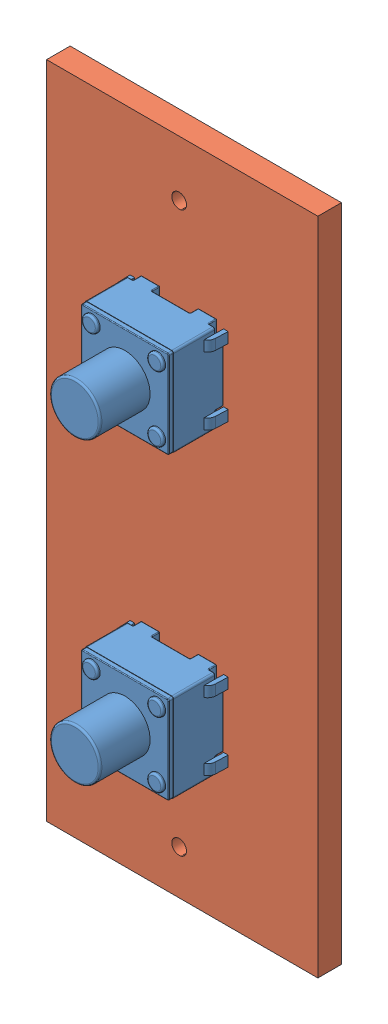
SolidWorks assembly tactile_switches, configuration Default. Lengths in mm.
Overall size (18.42 50 10.46).
3 component instances, 2 part files, 7 mates.
Components (placement in the parent):
- tactileswitch-short-1: tactileswitch-short [Default] at (-16.5128 4.5787 28.3133) x (1 0 0) z (0 -1 0) size (7.69 10.46 6.01)
- tactile_board-1: tactile_board [Default] at (-25.5128 -27.7413 26.7133) size (18.42 44.79 1.6)
- tactileswitch-short-2: tactileswitch-short [Default] at (-16.5128 -15.7413 28.3133) x (1 0 0) z (0 -1 0) size (7.69 10.46 6.01)
Mates (geometry in assembly coordinates):
- Concentric2: concentric anti-aligned: cone of tactileswitch-short-1 through (-16.5128 4.5787 31.9963) axis (0 0 1); cylinder of tactile_board-1 through (-16.5128 4.5787 28.3133) axis (0 0 -1) radius 1.5
- Coincident3: coincident anti-aligned: plane of tactileswitch-short-1 through (-17.8145 1.5752 28.3133) normal (0 0 -1); plane of tactile_board-1 through (-25.5128 -27.7413 28.3133) normal (0 0 1)
- Concentric3: concentric anti-aligned: cylinder of tactile_board-1 through (-16.5128 -15.7413 28.3133) axis (0 0 -1) radius 1.5; cone of tactileswitch-short-2 through (-16.5128 -15.7413 31.9963) axis (0 0 1)
- Coincident4: coincident anti-aligned: plane of tactile_board-1 through (-25.5128 -27.7413 28.3133) normal (0 0 1); plane of tactileswitch-short-2 through (-17.8145 -18.7448 28.3133) normal (0 0 -1)
- Parallel2: parallel aligned: plane of tactileswitch-short-1 through (-19.5163 1.5752 31.6915) normal (-1 0 0); plane of tactileswitch-short-2 through (-19.5163 -18.7448 31.6915) normal (-1 0 0)
- Concentric4: concentric anti-aligned: cylinder of wide_panel-1 through (-16.5128 4.5787 35.0042) axis (0 0 -1) radius 3.4; cone of tactileswitch-short-1 through (-16.5128 4.5787 31.9963) axis (0 0 1)
- Parallel4: parallel: plane of wide_panel-1 through (62.9872 56.4644 35.0042) normal (1 0 0); line of tactile_board-1 through (-7.0928 -27.7413 26.7133) axis (0 1 0)
